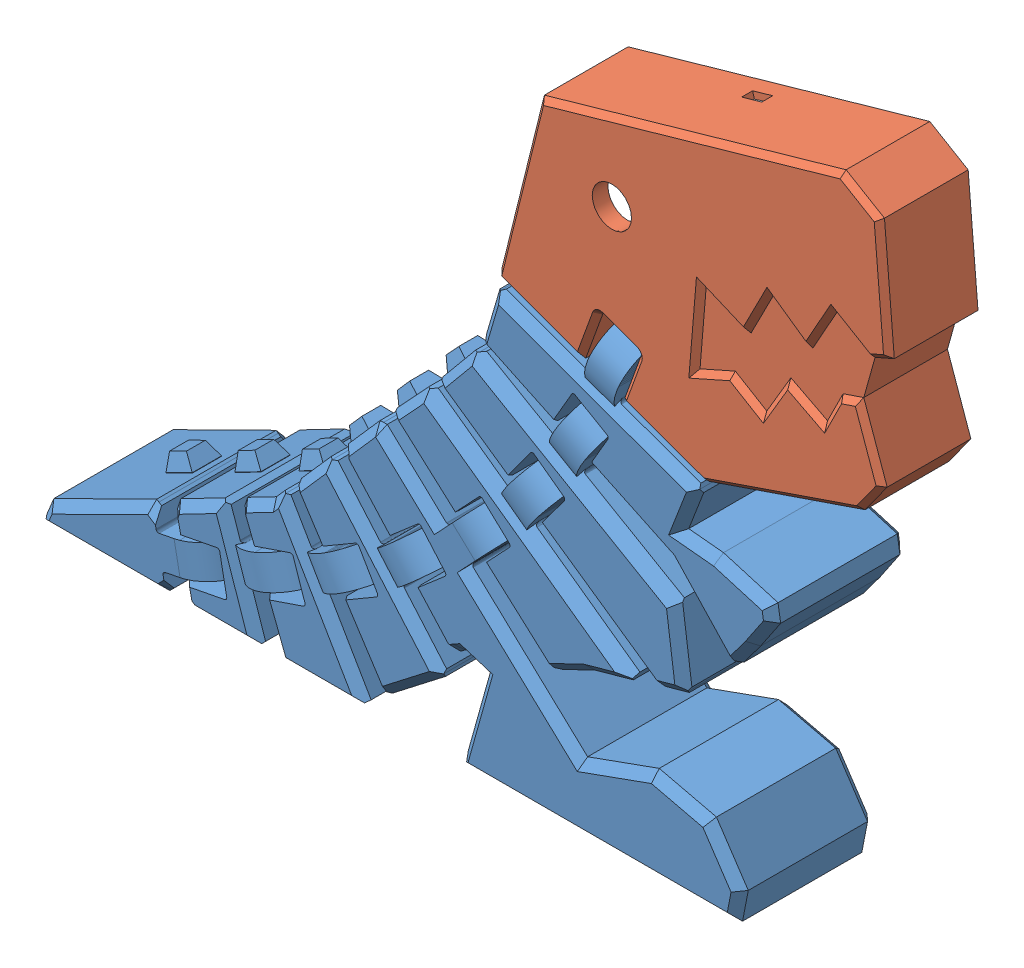
SolidWorks assembly MK2.2.3 Head+Body Assy, configuration Default. Lengths in mm.
Overall size (113.82 94.44 18.21).
3 component instances, 3 part files, 3 mates.
Components (placement in the parent):
- MK2.2.0 Body-1: MK2.2.0 Body [Default] at (-105.7885 20.8682 -7.5764) x (1 0.000012 0) z (0 0 1) size (98.19 60.49 18.21)
- MK2.2.3 Head Bottom-1: MK2.2.3 Head Bottom [Default] at (-105.785 20.8678 -7.5764) size (52.5 45.27 11.91)
- MK2.2.4 Head Top-1: MK2.2.4 Head Top [Default] at (-105.785 20.8678 -35.1846) size (52.37 45.27 11.9) (hidden)
Mates (geometry in assembly coordinates):
- Concentric1: concentric anti-aligned: cylinder of 1.4 Flexi Rex No Head by Lee + Connor-1 through (15.0442 -22.4059 1.5236) axis (-0.93963 0.342192 0) radius 2.8; cylinder of MK2.20 Head Bottom-1 through (-37.6835 -3.2036 1.5236) axis (0.93963 -0.342192 0) radius 2.1
- Coincident1: coincident aligned: plane of 1.4 Flexi Rex No Head by Lee + Connor-1 through (-105.7885 20.8682 10.6236) normal (0 0 1); plane of MK2.20 Head Bottom-1 through (-105.785 20.8678 10.6236) normal (0 0 1)
- Concentric2: concentric anti-aligned: cylinder of MK2.2.0 Head Bottom-1 through (-25.7601 12.4985 -1.4087) axis (0 0 1) radius 2.625; cylinder of MK2.2.2 Head Top-1 through (-25.7601 12.4985 -23.1523) axis (0 0 -1) radius 2.625
